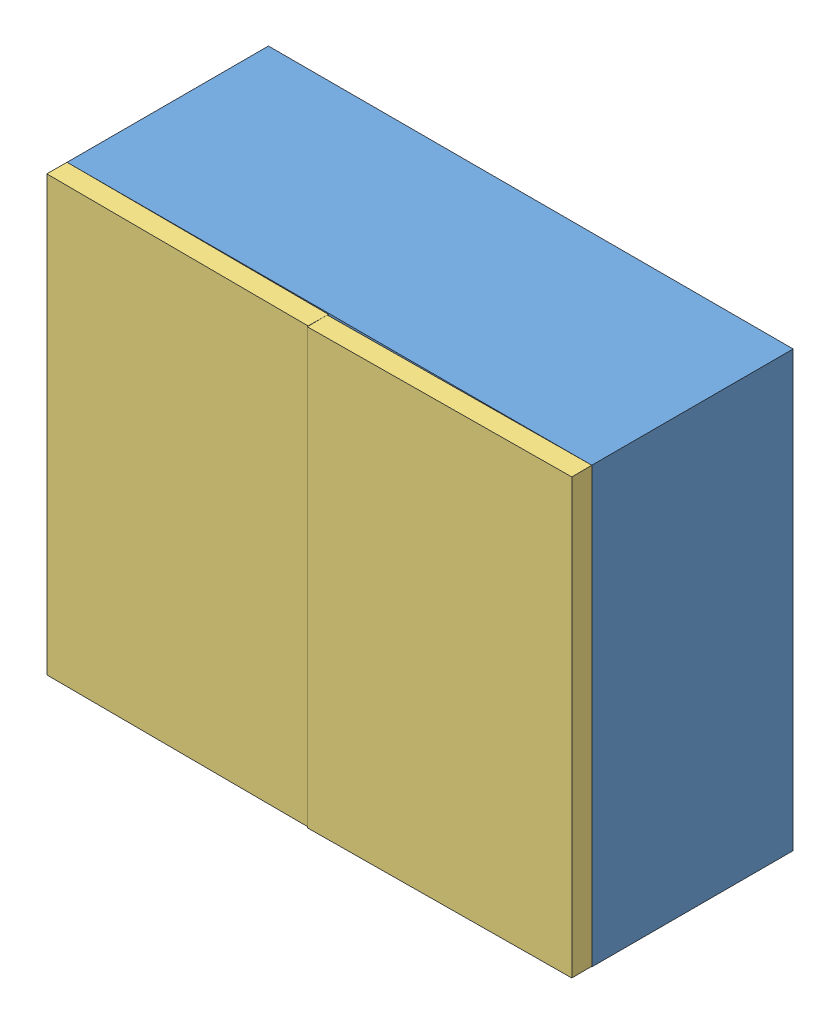
SolidWorks assembly reservoir jdid, configuration Default. Lengths in mm.
Overall size (131.88 107.88 58.77).
43 component instances, 3 part files, 10 mates.
Components (placement in the parent):
- reservoir jdid-1: reservoir jdid [Default] at (-33.9917 61.2911 67.9736) size (130.28 107.88 50)
- CERISE-1: CERISE [Default] at (-50.469 40.1926 79.2236) x (0.826261 -0.503518 0.252513) z (-0.252513 0.06962 0.965086) size (22.5 22.5 22.5)
- CERISE-2: CERISE [Default] at (-50.469 40.1926 101.7236) x (0.826261 -0.503518 0.252513) z (-0.252513 0.06962 0.965086) size (22.5 22.5 22.5)
- CERISE-3: CERISE [Default] at (-27.969 40.1926 101.7236) x (0.826261 -0.503518 0.252513) z (-0.252513 0.06962 0.965086) size (22.5 22.5 22.5)
- CERISE-4: CERISE [Default] at (-5.469 40.1926 101.7236) x (0.826261 -0.503518 0.252513) z (-0.252513 0.06962 0.965086) size (22.5 22.5 22.5)
- CERISE-5: CERISE [Default] at (17.031 40.1926 101.7236) x (0.826261 -0.503518 0.252513) z (-0.252513 0.06962 0.965086) size (22.5 22.5 22.5)
- CERISE-6: CERISE [Default] at (39.531 40.1926 101.7236) x (0.826261 -0.503518 0.252513) z (-0.252513 0.06962 0.965086) size (22.5 22.5 22.5)
- CERISE-7: CERISE [Default] at (-50.469 62.6926 101.7236) x (0.826261 -0.503518 0.252513) z (-0.252513 0.06962 0.965086) size (22.5 22.5 22.5)
- CERISE-8: CERISE [Default] at (-27.969 62.6926 101.7236) x (0.826261 -0.503518 0.252513) z (-0.252513 0.06962 0.965086) size (22.5 22.5 22.5)
- CERISE-9: CERISE [Default] at (-5.469 62.6926 101.7236) x (0.826261 -0.503518 0.252513) z (-0.252513 0.06962 0.965086) size (22.5 22.5 22.5)
- CERISE-10: CERISE [Default] at (17.031 62.6926 101.7236) x (0.826261 -0.503518 0.252513) z (-0.252513 0.06962 0.965086) size (22.5 22.5 22.5)
- CERISE-11: CERISE [Default] at (39.531 62.6926 101.7236) x (0.826261 -0.503518 0.252513) z (-0.252513 0.06962 0.965086) size (22.5 22.5 22.5)
- CERISE-12: CERISE [Default] at (-50.469 85.1926 101.7236) x (0.826261 -0.503518 0.252513) z (-0.252513 0.06962 0.965086) size (22.5 22.5 22.5)
- CERISE-13: CERISE [Default] at (-27.969 85.1926 101.7236) x (0.826261 -0.503518 0.252513) z (-0.252513 0.06962 0.965086) size (22.5 22.5 22.5)
- CERISE-14: CERISE [Default] at (-5.469 85.1926 101.7236) x (0.826261 -0.503518 0.252513) z (-0.252513 0.06962 0.965086) size (22.5 22.5 22.5)
- CERISE-15: CERISE [Default] at (17.031 85.1926 101.7236) x (0.826261 -0.503518 0.252513) z (-0.252513 0.06962 0.965086) size (22.5 22.5 22.5)
- CERISE-16: CERISE [Default] at (39.531 85.1926 101.7236) x (0.826261 -0.503518 0.252513) z (-0.252513 0.06962 0.965086) size (22.5 22.5 22.5)
- CERISE-17: CERISE [Default] at (-50.469 107.6926 101.7236) x (0.826261 -0.503518 0.252513) z (-0.252513 0.06962 0.965086) size (22.5 22.5 22.5)
- CERISE-18: CERISE [Default] at (-27.969 107.6926 101.7236) x (0.826261 -0.503518 0.252513) z (-0.252513 0.06962 0.965086) size (22.5 22.5 22.5)
- CERISE-19: CERISE [Default] at (-5.469 107.6926 101.7236) x (0.826261 -0.503518 0.252513) z (-0.252513 0.06962 0.965086) size (22.5 22.5 22.5)
- CERISE-20: CERISE [Default] at (17.031 107.6926 101.7236) x (0.826261 -0.503518 0.252513) z (-0.252513 0.06962 0.965086) size (22.5 22.5 22.5)
- CERISE-21: CERISE [Default] at (39.531 107.6926 101.7236) x (0.826261 -0.503518 0.252513) z (-0.252513 0.06962 0.965086) size (22.5 22.5 22.5)
- CERISE-22: CERISE [Default] at (-27.969 40.1926 79.2236) x (0.826261 -0.503518 0.252513) z (-0.252513 0.06962 0.965086) size (22.5 22.5 22.5)
- CERISE-23: CERISE [Default] at (-5.469 40.1926 79.2236) x (0.826261 -0.503518 0.252513) z (-0.252513 0.06962 0.965086) size (22.5 22.5 22.5)
- CERISE-24: CERISE [Default] at (17.031 40.1926 79.2236) x (0.826261 -0.503518 0.252513) z (-0.252513 0.06962 0.965086) size (22.5 22.5 22.5)
- CERISE-25: CERISE [Default] at (39.531 40.1926 79.2236) x (0.826261 -0.503518 0.252513) z (-0.252513 0.06962 0.965086) size (22.5 22.5 22.5)
- CERISE-26: CERISE [Default] at (-50.469 62.6926 79.2236) x (0.826261 -0.503518 0.252513) z (-0.252513 0.06962 0.965086) size (22.5 22.5 22.5)
- CERISE-27: CERISE [Default] at (-27.969 62.6926 79.2236) x (0.826261 -0.503518 0.252513) z (-0.252513 0.06962 0.965086) size (22.5 22.5 22.5)
- CERISE-28: CERISE [Default] at (-5.469 62.6926 79.2236) x (0.826261 -0.503518 0.252513) z (-0.252513 0.06962 0.965086) size (22.5 22.5 22.5)
- CERISE-29: CERISE [Default] at (17.031 62.6926 79.2236) x (0.826261 -0.503518 0.252513) z (-0.252513 0.06962 0.965086) size (22.5 22.5 22.5)
- CERISE-30: CERISE [Default] at (39.531 62.6926 79.2236) x (0.826261 -0.503518 0.252513) z (-0.252513 0.06962 0.965086) size (22.5 22.5 22.5)
- CERISE-31: CERISE [Default] at (-50.469 85.1926 79.2236) x (0.826261 -0.503518 0.252513) z (-0.252513 0.06962 0.965086) size (22.5 22.5 22.5)
- CERISE-32: CERISE [Default] at (-27.969 85.1926 79.2236) x (0.826261 -0.503518 0.252513) z (-0.252513 0.06962 0.965086) size (22.5 22.5 22.5)
- CERISE-33: CERISE [Default] at (-5.469 85.1926 79.2236) x (0.826261 -0.503518 0.252513) z (-0.252513 0.06962 0.965086) size (22.5 22.5 22.5)
- CERISE-34: CERISE [Default] at (17.031 85.1926 79.2236) x (0.826261 -0.503518 0.252513) z (-0.252513 0.06962 0.965086) size (22.5 22.5 22.5)
- CERISE-35: CERISE [Default] at (39.531 85.1926 79.2236) x (0.826261 -0.503518 0.252513) z (-0.252513 0.06962 0.965086) size (22.5 22.5 22.5)
- CERISE-36: CERISE [Default] at (-50.469 107.6926 79.2236) x (0.826261 -0.503518 0.252513) z (-0.252513 0.06962 0.965086) size (22.5 22.5 22.5)
- CERISE-37: CERISE [Default] at (-27.969 107.6926 79.2236) x (0.826261 -0.503518 0.252513) z (-0.252513 0.06962 0.965086) size (22.5 22.5 22.5)
- CERISE-38: CERISE [Default] at (-5.469 107.6926 79.2236) x (0.826261 -0.503518 0.252513) z (-0.252513 0.06962 0.965086) size (22.5 22.5 22.5)
- CERISE-39: CERISE [Default] at (17.031 107.6926 79.2236) x (0.826261 -0.503518 0.252513) z (-0.252513 0.06962 0.965086) size (22.5 22.5 22.5)
- CERISE-40: CERISE [Default] at (39.531 107.6926 79.2236) x (0.826261 -0.503518 0.252513) z (-0.252513 0.06962 0.965086) size (22.5 22.5 22.5)
- beb-1: beb [Default] at (-33.992 61.2911 118.1078) x (0.999992 0 0.004099) z (-0.004099 0 0.999992) size (65.14 107.74 5)
- beb-2: beb [Default] at (31.1512 61.2911 118.2422) x (0.999966 0 -0.008287) z (0.008287 0 0.999966) size (65.14 107.74 5)
Mates (geometry in assembly coordinates):
- Tangent1: tangent anti-aligned: plane of reservoir jdid-1 through (-61.719 126.8212 117.9736) normal (1 0 0); sphere of CERISE-1
- Tangent2: tangent aligned: plane of reservoir jdid-1 through (-33.9917 61.2911 67.9736) normal (0 0 -1); sphere of CERISE-1
- Tangent3: tangent anti-aligned: plane of reservoir jdid-1 through (-61.719 28.9426 117.9736) normal (0 1 0); sphere of CERISE-1
- Tangent4: tangent anti-aligned: plane of reservoir jdid-1 through (-61.719 28.9426 117.9736) normal (0 1 0); sphere of CERISE-2
- Tangent5: tangent anti-aligned: plane of reservoir jdid-1 through (-61.719 126.8212 117.9736) normal (1 0 0); sphere of CERISE-2
- Tangent6: tangent anti-aligned: sphere of CERISE-1; sphere of CERISE-2
- Coincident4: coincident aligned: line of reservoir jdid-1 through (-66.719 131.8212 117.9736) axis (0 -1 0); line of Part3^Assem1-1 through (-66.719 131.8212 117.9736) axis (0 -1 0)
- Coincident5: coincident: line of reservoir jdid-1 through (-66.719 131.8212 117.9736) axis (0 0 -1); point of Part3^Assem1-1
- Coincident6: coincident aligned: line of reservoir jdid-1 through (63.5647 23.9426 117.9736) axis (0 1 0); line of Part3^Assem1-2 through (63.5647 24.0856 117.9736) axis (0 1 0)
- Coincident7: coincident: point of reservoir jdid-1; point of Part3^Assem1-2
